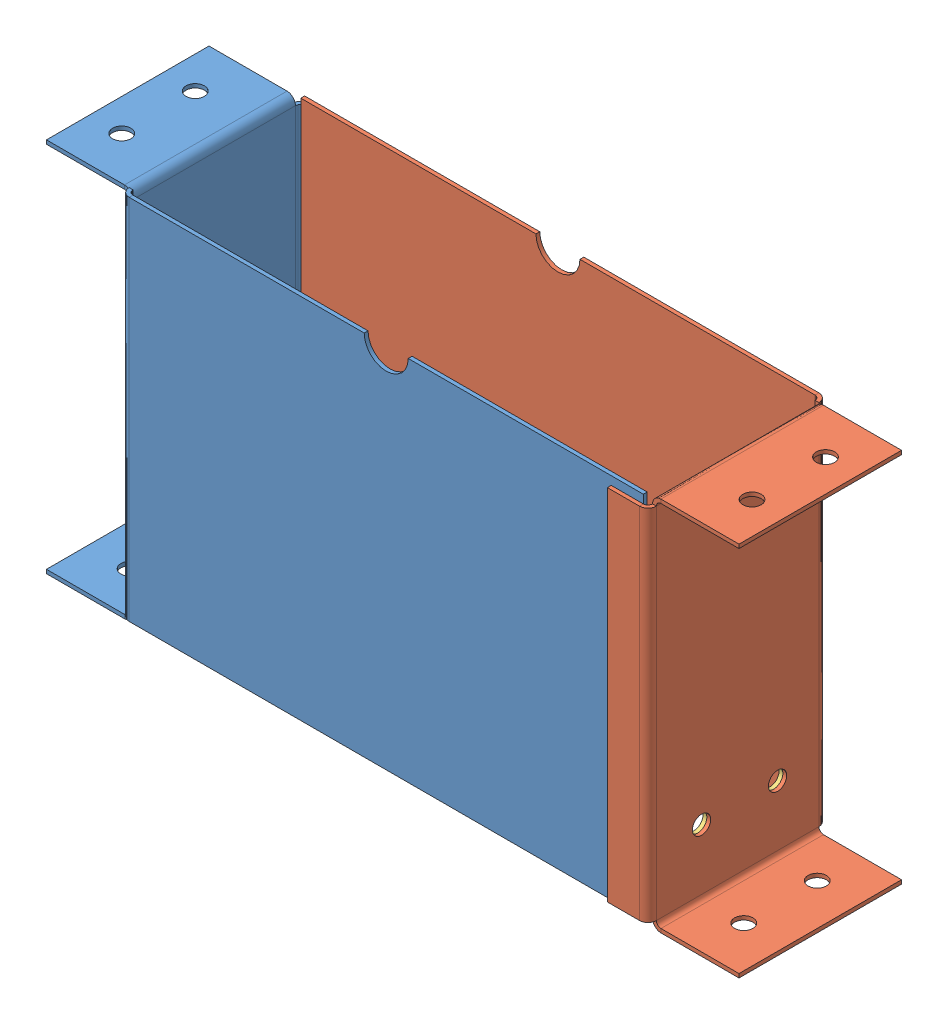
SolidWorks assembly Bottom Assembly Design 6.2, configuration Default. Lengths in mm.
Overall size (481.56 259.83 126.72).
3 component instances, 3 part files, 8 mates.
Components (placement in the parent):
- Bottom Assembly - Casing Side 1.2-1: Bottom Assembly - Casing Side 1.2 [Default] at (19.4485 98.189 475.1792) size (418.58 259.83 124.06)
- Bottom Assembly - Casing Side 2.2-1: Bottom Assembly - Casing Side 2.2 [Default] at (375.0485 98.189 353.7774) x (-1 0 0) z (0 0 -1) size (418.58 259.83 124.06)
- Bottom Assembly - Mesh with Screw Holes-1: Bottom Assembly - Mesh with Screw Holes [Default] at (16.2735 174.389 472.5224) size (361.95 53.46 116.09)
Mates (geometry in assembly coordinates):
- Parallel1: parallel anti-aligned: plane of Bottom Assembly - Casing Side 1.2-1 through (197.2485 352.189 472.5224) normal (0 0 -1); plane of Bottom Assembly - Casing Side 2.2-1 through (197.2485 352.189 356.4342) normal (0 0 1)
- Parallel2: parallel anti-aligned: line of Bottom Assembly - Casing Side 1.2-1 through (182.0085 352.189 472.5224) axis (-1 0 0); line of Bottom Assembly - Casing Side 2.2-1 through (212.4885 352.189 353.7774) axis (1 0 0)
- Coincident3: coincident anti-aligned: plane of Bottom Assembly - Casing Side 1.2-1 through (19.4485 98.189 353.7774) normal (0 0 1); plane of Bottom Assembly - Casing Side 2.2-1 through (197.2485 352.189 353.7774) normal (0 0 -1)
- Coincident4: coincident aligned: line of Bottom Assembly - Casing Side 1.2-1 through (375.0485 98.189 475.1792) axis (0 1 0); line of Bottom Assembly - Casing Side 2.2-1 through (375.0485 98.189 475.1792) axis (0 1 0)
- Coincident5: coincident aligned: line of Bottom Assembly - Casing Side 1.2-1 through (375.0485 98.189 472.5224) axis (0 0 1); line of Bottom Assembly - Casing Side 2.2-1 through (375.0485 98.189 475.1792) axis (0 0 1)
- Coincident6: coincident anti-aligned: plane of Bottom Assembly - Casing Side 2.2-1 through (378.2235 98.189 353.7774) normal (-1 0 0); plane of Bottom Assembly - Mesh with Screw Holes-1 through (378.2235 174.389 472.5224) normal (1 0 0)
- Coincident7: coincident anti-aligned: line of Bottom Assembly - Casing Side 1.2-1 through (375.0485 174.389 472.5224) axis (-1 0 0); line of Bottom Assembly - Mesh with Screw Holes-1 through (22.1054 174.389 472.5224) axis (1 0 0)
- Parallel3: parallel anti-aligned: plane of Bottom Assembly - Casing Side 2.2-1 through (197.2485 352.189 356.4342) normal (0 0 1); plane of Bottom Assembly - Mesh with Screw Holes-1 through (16.2735 171.7321 356.4342) normal (0 0 -1)
